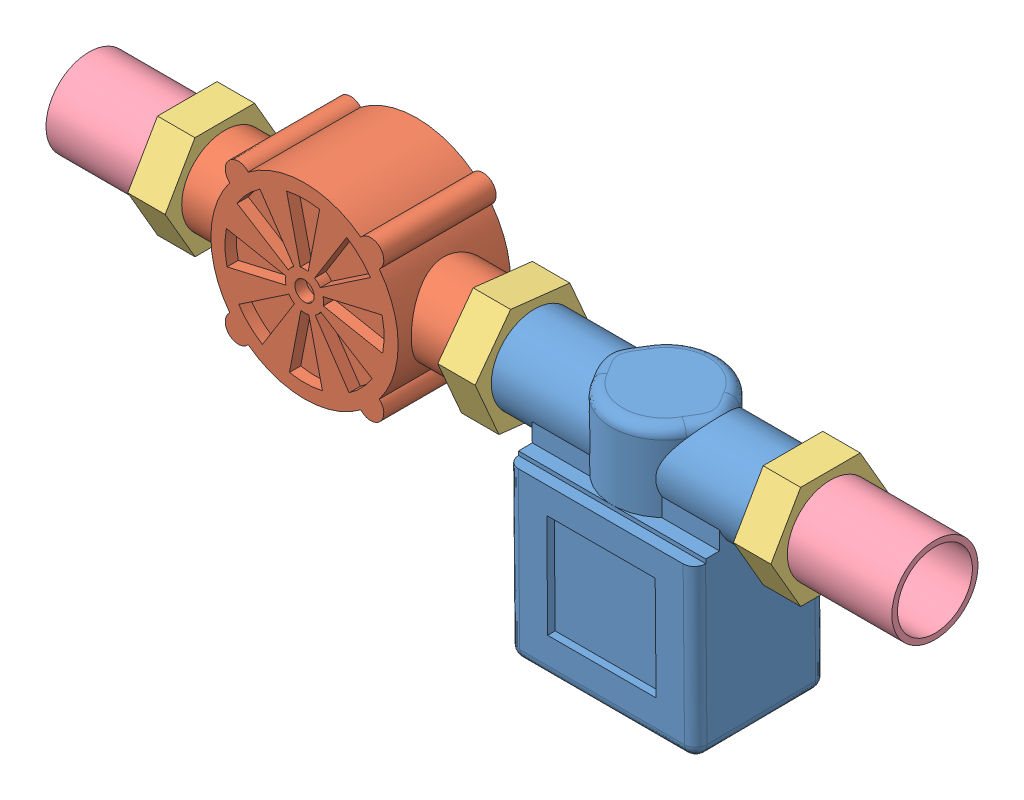
SolidWorks assembly sistema, configuration Predeterminado. Lengths in mm.
Overall size (225.84 80.15 35.58).
7 component instances, 4 part files, 6 mates.
Components (placement in the parent):
- valvula de agua-1: valvula de agua [Predeterminado] at (-50.6637 26.5798 0.3074) x (1 0 0) z (0 -0.999962 -0.008727) size (80 35 67.07)
- sensor de flujo-1: sensor de flujo [Predeterminado] at (-132.1637 36.5794 0.3946) x (1 0 0) z (0 0 -1) size (83 50 31)
- tuerca-1: tuerca [Predeterminado] at (-168.4528 36.5794 0.3946) x (0 0 1) z (-1 0 0) size (31.82 27.57 10)
- tuerca-2: tuerca [Predeterminado] at (-85.7899 36.5794 0.3946) x (0 0.113203 0.993572) z (-1 0 0) size (31.82 27.57 10)
- tuerca-3: tuerca [Predeterminado] at (-6.7422 36.5794 0.3946) x (0 0 1) z (-1 0 0) size (31.82 27.57 10)
- tubo de media-1: tubo de media [Predeterminado] at (6.1516 36.5794 0.3946) x (0 0 -1) z (1 0 0) size (23 23 30)
- tubo de media-2: tubo de media [Predeterminado] at (-189.6874 36.5794 0.3946) x (0 0 1) z (-1 0 0) size (23 23 30)
Mates (geometry in assembly coordinates):
- Coincidente1: coincident aligned: circle of valvula de agua-1; circle of sensor de flujo-1
- Concéntrica1: concentric anti-aligned: circle of sensor de flujo-1; circle of tuerca-2
- Concéntrica2: concentric anti-aligned: circle of valvula de agua-1; circle of tuerca-3
- Concéntrica3: concentric anti-aligned: circle of sensor de flujo-1; circle of tuerca-1
- Concéntrica4: concentric aligned: circle of valvula de agua-1; circle of tubo de media-1
- Concéntrica5: concentric anti-aligned: circle of sensor de flujo-1; circle of tubo de media-2
